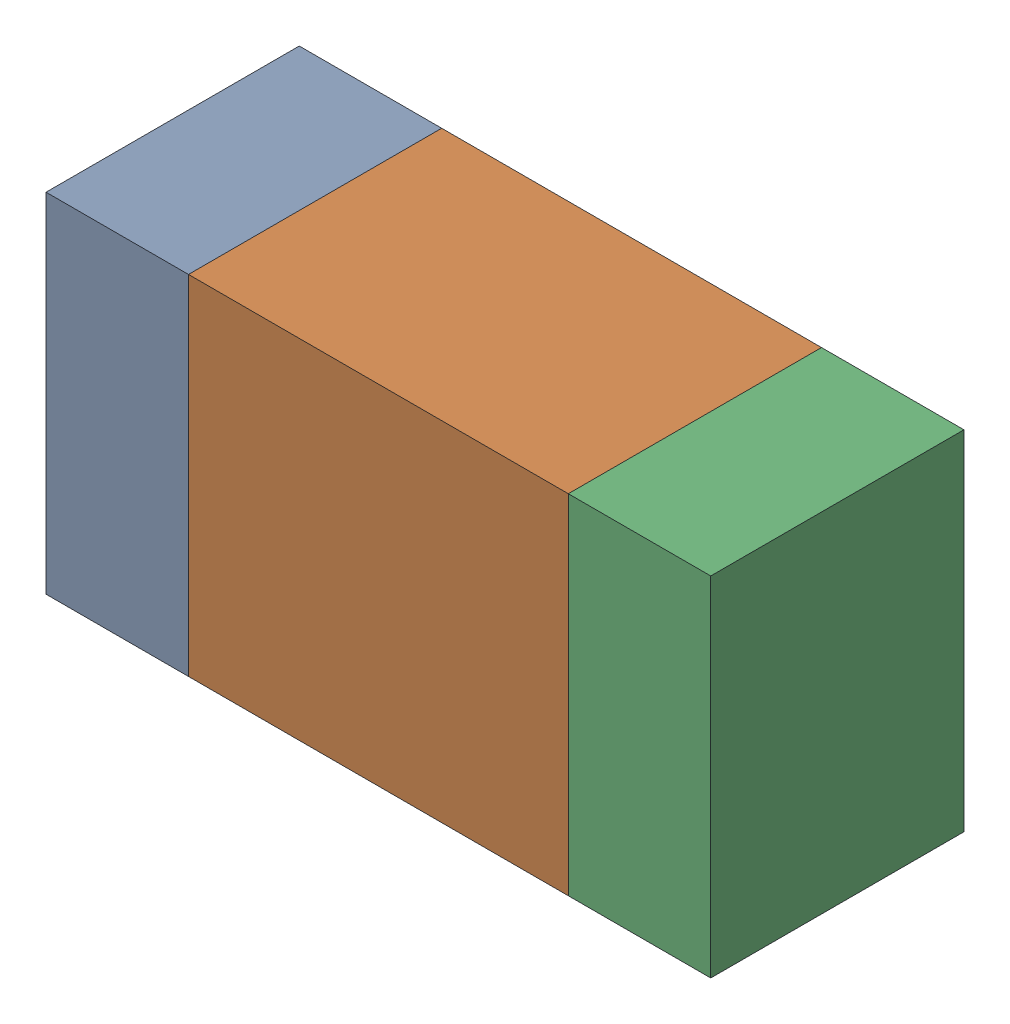
SolidWorks assembly R116_2PCB, configuration Default. Lengths in mm.
Overall size (1.05 0.55 0.4).
6 component instances, 2 part files, 0 mates.
Components (placement in the parent):
- 854785432-1: 854785432 [Default] at (98.8876 94.9001 0) size (0.22 0.55 0.4)
  - Extruded-1: Extruded [Default] at origin size (0.22 0.55 0.4)
- 854785568-1: 854785568 [Default] at (99.3001 94.9001 0) size (0.6 0.55 0.4)
  - Extruded_2-1: Extruded_2 [Default] at origin size (0.6 0.55 0.4)
- 854785432-2: 854785432 [Default] at (99.7126 94.9001 0) size (0.22 0.55 0.4)
  - Extruded-1: Extruded [Default] at origin size (0.22 0.55 0.4)
